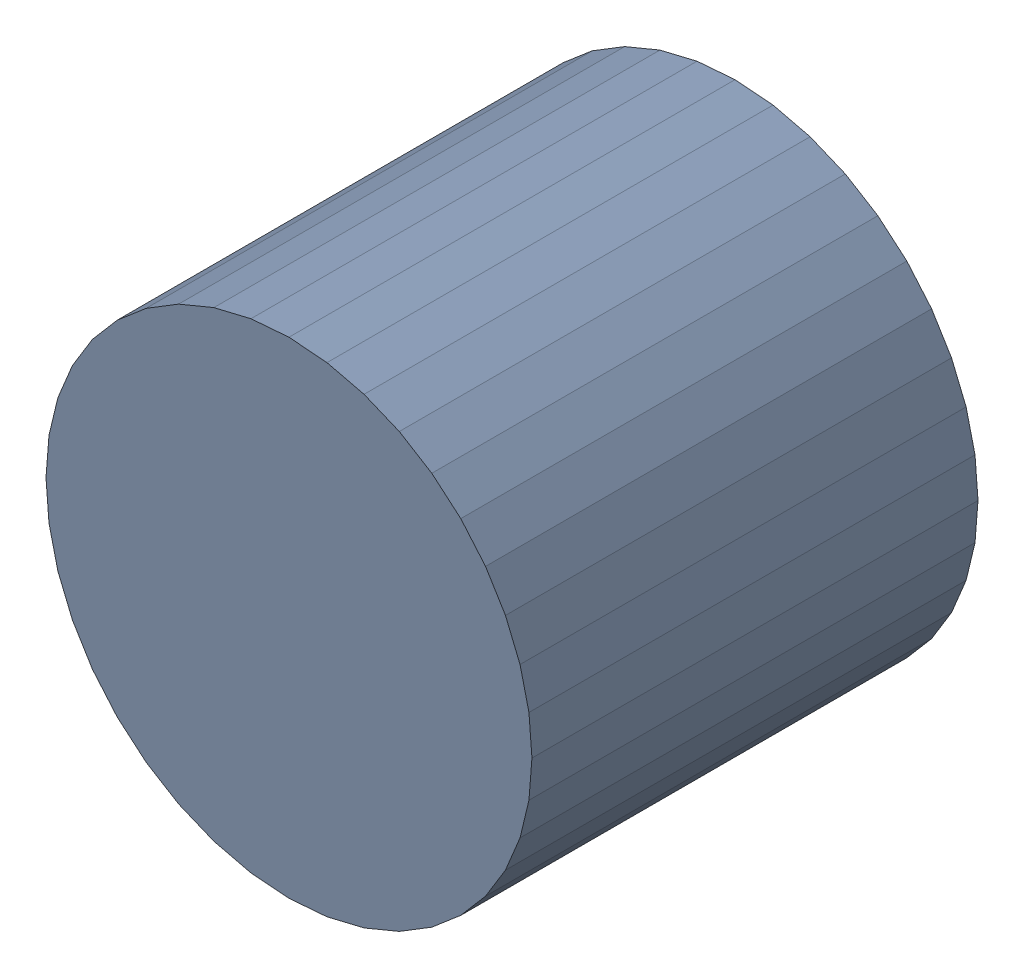
SolidWorks assembly C10_Motor_5Kanaloa_v2.0.0_Motor, configuration Default. Lengths in mm.
Overall size (6.32 6.32 5.8).
2 component instances, 1 part files, 0 mates.
Components (placement in the parent):
- 352892112-1: 352892112 [Default] at (131.513 72.39 0) size (6.32 6.32 5.8)
  - Extruded_11-1: Extruded_11 [Default] at origin size (6.32 6.32 5.8)
